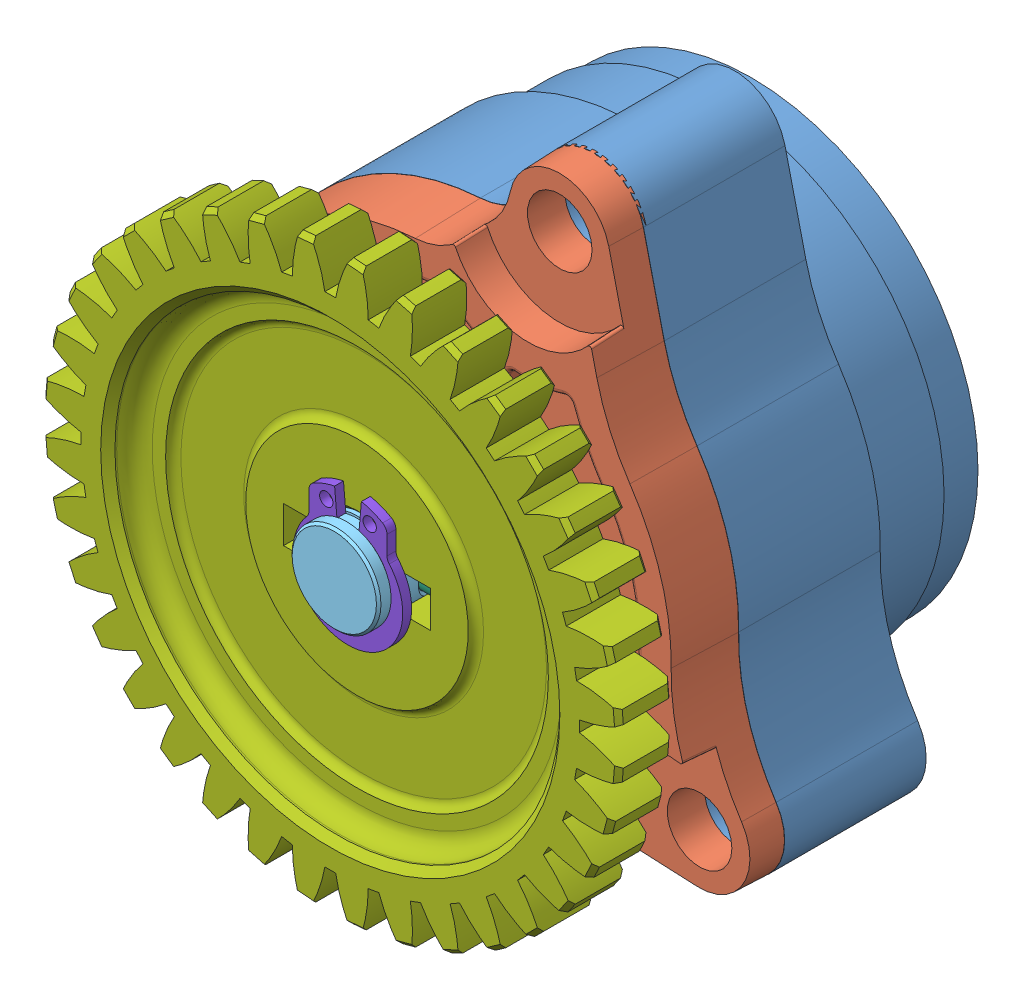
SolidWorks assembly oil_pump, configuration Default. Lengths in mm.
Overall size (64.95 70.46 48.85).
9 component instances, 8 part files, 13 mates.
Components (placement in the parent):
- housing-1: housing [Default] at (-78.0877 64.9401 99.0883) size (64.95 68.76 30.51)
- cover-1: cover [Default] at (-78.0877 64.9401 114.6925) size (64.95 66.25 9.25)
- outer rotor-1: outer rotor [Default] at (-78.0877 68.1151 114.2367) x (-1 0 0) z (0 0 -1) size (40.51 40.51 21.97)
- inner rotor-1: inner rotor [Default] at (-78.0877 64.9401 114.2367) x (-1 0 0) z (0 0 -1) size (29.46 29.46 21.97)
- shaft-1: shaft [Default] at (-78.0877 64.9401 133.1343) x (0 1 0) z (0 0 -1) size (9.98 10.18 48.39)
- pin-1: pin [Default] at (-78.0877 64.9401 101.0033) x (0 0 -1) z (1 0 0) size (3.99 3.99 15.67)
- gear-1: gear [Default] at (-78.0877 64.9401 130.5343) size (64.86 64.86 10.7)
- pin-2: pin [Default] at (-78.0877 64.9401 126.4033) x (0 0.018541 -0.999828) z (1 0 0) size (3.99 3.99 15.67)
- retaining ring-1: retaining ring [Default] at (-78.0877 64.0003 130.5943) size (12.3 14.71 1)
Mates (geometry in assembly coordinates):
- MateDistance1: distance = 0.01 mm anti-aligned: plane of housing-1 through (-78.0877 68.1151 92.2557) normal (0 0 1); plane of outer rotor-1 through (-78.0877 68.1151 92.2657) normal (0 0 -1)
- MateConcentric1: concentric aligned: cylinder of housing-1 through (-78.0877 68.1151 92.2557) axis (0 0 1) radius 20.32; cylinder of outer rotor-1 through (-78.0877 68.1151 92.2657) axis (0 0 1) radius 20.2565
- MateConcentric2: concentric anti-aligned: cylinder of housing-1 through (-78.0877 64.9401 115.2427) axis (0 0 -1) radius 4.8895; cylinder of cover-1 through (-78.0877 64.9401 114.6925) axis (0 0 1) radius 5.0165
- MateConcentric3: concentric anti-aligned: cylinder of housing-1 through (-78.0877 64.9401 115.2427) axis (0 0 -1) radius 4.8895; cylinder of inner rotor-1 through (-78.0877 64.9401 92.2657) axis (0 0 1) radius 5.0038
- MateDistance3: distance = 0.01 mm anti-aligned: plane of housing-1 through (-78.0877 68.1151 92.2557) normal (0 0 1); plane of inner rotor-1 through (-92.2835 73.0398 92.2657) normal (0 0 -1)
- MateCoincident1: coincident aligned: plane of inner rotor-1; plane of shaft-1
- MateCoincident2: coincident aligned: plane of shaft-1; plane of pin-1 through (-78.0877 64.9401 101.0033) normal (1 0 0)
- MateCoincident3: coincident aligned: plane of shaft-1; plane of pin-2 through (-78.0877 64.9401 126.4033) normal (1 0 0)
- MateParallel1: parallel aligned: plane of pin-1; plane of gear-1 through (-78.0877 64.9401 130.5343) normal (0 1 0)
- MateDistance5: distance = 0.05 mm anti-aligned: plane of housing-1 through (-78.0877 64.9401 113.6425) normal (0 0 1); plane of cover-1 through (-78.0877 64.9401 113.6925) normal (0 0 -1)
- MateDistance6: distance = 0.01 mm anti-aligned: plane of gear-1 through (-78.0877 64.9401 130.5843) normal (0 0 1); plane of retaining ring-1 through (-78.0877 64.9401 130.5943) normal (0 0 -1)
- Concentric1: concentric aligned: cylinder of housing-1 through (-78.0877 64.9401 115.2427) axis (0 0 -1) radius 4.8895; cylinder of gear-1 through (-78.0877 64.9401 133.5843) axis (0 0 -1) radius 5
- Distance1: distance = 12.2416 mm anti-aligned: plane of housing-1 through (-67.1315 97.1644 115.2427) normal (0 0 1); plane of gear-1 through (-78.0877 64.9401 127.4843) normal (0 0 -1)
